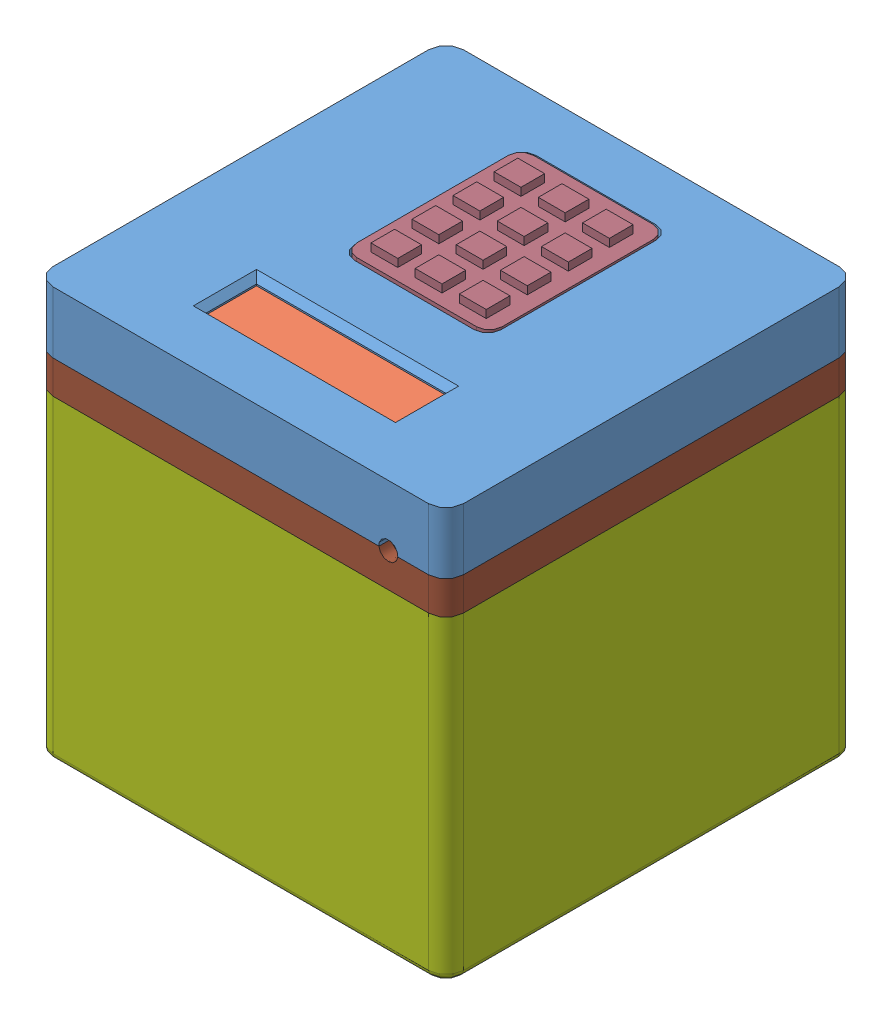
SolidWorks assembly Housing ASSY ALL, configuration Default. Lengths in mm.
Overall size (138.97 132.9 133.29).
197 component instances, 47 part files, 16 mates.
Components (placement in the parent):
- Housing ASSY TOP-1: Housing ASSY TOP [Default] at (34.8394 204.6512 120.8885) x (1 0 0) z (0 0 -1) size (130 68.9 130)
  - Housing-Top-1: Housing-Top [Default] at (0.5206 130 -0.9544) size (130 20 130)
  - LCD cover-1: LCD cover [Default] at (0.5206 132.5 -38.9544) size (83 2.5 39)
  - PCB ASSY-2: PCB ASSY [Default] at (-38.2241 57.9274 36.8538) x (1 0 0) z (0 1 0) size (111.4 79.3 20.98)
    - pcb-1: pcb [Default] at (-55.2553 -31.6918 89.0126) size (111.4 79.3 4.54)
    - pin header double row- 20 contacts-2: pin header double row- 20 contacts [Default] at (31.3735 92.5733 87.6126) x (1 0 0) z (0 1 0) size (2.54 11.54 2.54)
    - pin header double row- 20 contacts-28: pin header double row- 20 contacts [Default] at (33.9135 92.5733 87.6126) x (1 0 0) z (0 1 0) size (2.54 11.54 2.54)
    - pin header double row- 20 contacts-29: pin header double row- 20 contacts [Default] at (36.4535 92.5733 87.6126) x (1 0 0) z (0 1 0) size (2.54 11.54 2.54)
    - pin header double row- 20 contacts-30: pin header double row- 20 contacts [Default] at (38.9935 92.5733 87.6126) x (1 0 0) z (0 1 0) size (2.54 11.54 2.54)
    - pin header double row- 20 contacts-31: pin header double row- 20 contacts [Default] at (41.5335 92.5733 87.6126) x (1 0 0) z (0 1 0) size (2.54 11.54 2.54)
    - pin header double row- 20 contacts-32: pin header double row- 20 contacts [Default] at (44.0735 92.5733 87.6126) x (1 0 0) z (0 1 0) size (2.54 11.54 2.54)
    - pin header double row- 20 contacts-33: pin header double row- 20 contacts [Default] at (46.6135 92.5733 87.6126) x (1 0 0) z (0 1 0) size (2.54 11.54 2.54)
    - pin header double row- 20 contacts-34: pin header double row- 20 contacts [Default] at (49.1535 92.5733 87.6126) x (1 0 0) z (0 1 0) size (2.54 11.54 2.54)
    - pin header double row- 20 contacts-35: pin header double row- 20 contacts [Default] at (51.6935 92.5733 87.6126) x (1 0 0) z (0 1 0) size (2.54 11.54 2.54)
    - pin header double row- 20 contacts-36: pin header double row- 20 contacts [Default] at (54.2335 92.5733 87.6126) x (1 0 0) z (0 1 0) size (2.54 11.54 2.54)
    - pin header double row- 20 contacts-37: pin header double row- 20 contacts [Default] at (56.7735 92.5733 87.6126) x (1 0 0) z (0 1 0) size (2.54 11.54 2.54)
    - pin header double row- 20 contacts-38: pin header double row- 20 contacts [Default] at (59.3135 92.5733 87.6126) x (1 0 0) z (0 1 0) size (2.54 11.54 2.54)
    - pin header double row- 20 contacts-39: pin header double row- 20 contacts [Default] at (61.8535 92.5733 87.6126) x (1 0 0) z (0 1 0) size (2.54 11.54 2.54)
    - pin header double row- 20 contacts-40: pin header double row- 20 contacts [Default] at (64.3935 92.5733 87.6126) x (1 0 0) z (0 1 0) size (2.54 11.54 2.54)
    - pin header double row- 20 contacts-41: pin header double row- 20 contacts [Default] at (66.9335 92.5733 87.6126) x (1 0 0) z (0 1 0) size (2.54 11.54 2.54)
    - pin header double row- 20 contacts-42: pin header double row- 20 contacts [Default] at (69.4735 92.5733 87.6126) x (1 0 0) z (0 1 0) size (2.54 11.54 2.54)
    - pj-072c-smt-1: pj-072c-smt [Default] at (85.4947 95.3082 91.3126) x (-1 0 0) z (0 1 0) size (5.8 5.75 10.4)
      - pj-072c-smt_01-1: pj-072c-smt_01 [Default] at origin size (5.8 5.75 3.2)
      - pj-072c-smt_02-1: pj-072c-smt_02 [Default] at origin size (1.2 3 3.2)
      - pj-072c-smt_03-1: pj-072c-smt_03 [Default] at origin size (1.45 4.4 3.2)
      - pj-072c-smt_04-1: pj-072c-smt_04 [Default] at origin size (5.7 5.75 9.6)
    - LCD spacer-1: LCD spacer [Default] at (76.2447 91.3082 87.6126) x (0 1 0) z (-1 0 0) size (5 2.54 5)
    - LCD spacer-2: LCD spacer [Default] at (76.2447 60.3082 85.0726) x (1 0 0) z (0 -1 0) size (5 2.54 5)
    - LCD spacer-3: LCD spacer [Default] at (1.2447 60.3082 85.0726) x (1 0 0) z (0 -1 0) size (5 2.54 5)
    - LCD spacer-4: LCD spacer [Default] at (1.2447 91.3082 85.0726) x (1 0 0) z (0 -1 0) size (5 2.54 5)
    - 16x2 Lcd display dsgn arch 2016-edit-00-1: 16x2 Lcd display dsgn arch 2016-edit-00 [Default] at (38.7447 75.8082 83.5726) x (1 0 0) z (0 0 -1) size (80 36 8.5)
    - pin header double row- 20 contacts-43: pin header double row- 20 contacts [Default] at (45.0911 54.5782 87.6126) x (1 0 0) z (0 1 0) size (2.54 11.54 2.54)
    - pin header double row- 20 contacts-44: pin header double row- 20 contacts [Default] at (42.5511 54.5782 87.6126) x (1 0 0) z (0 1 0) size (2.54 11.54 2.54)
    - pin header double row- 20 contacts-45: pin header double row- 20 contacts [Default] at (40.0111 54.5782 87.6126) x (1 0 0) z (0 1 0) size (2.54 11.54 2.54)
    - pin header double row- 20 contacts-46: pin header double row- 20 contacts [Default] at (37.4711 54.5782 87.6126) x (1 0 0) z (0 1 0) size (2.54 11.54 2.54)
    - pin header double row- 20 contacts-47: pin header double row- 20 contacts [Default] at (34.9311 54.5782 87.6126) x (1 0 0) z (0 1 0) size (2.54 11.54 2.54)
    - pin header double row- 20 contacts-48: pin header double row- 20 contacts [Default] at (32.3911 54.5782 87.6126) x (1 0 0) z (0 1 0) size (2.54 11.54 2.54)
    - pin header double row- 20 contacts-49: pin header double row- 20 contacts [Default] at (29.8511 54.5782 87.6126) x (1 0 0) z (0 1 0) size (2.54 11.54 2.54)
    - pin header double row- 20 contacts-50: pin header double row- 20 contacts [Default] at (-3.1653 45.0418 89.0126) x (1 0 0) z (0 -1 0) size (2.54 11.54 2.54)
    - pin header double row- 20 contacts-51: pin header double row- 20 contacts [Default] at (-1.3422 35.5094 89.0126) x (1 0 0) z (0 -1 0) size (2.54 11.54 2.54)
    - pin header double row- 20 contacts-52: pin header double row- 20 contacts [Default] at (-0.4792 26.6283 89.0126) x (1 0 0) z (0 -1 0) size (2.54 11.54 2.54)
    - pin header double row- 20 contacts-53: pin header double row- 20 contacts [Default] at (17.5747 25.2818 89.0126) x (1 0 0) z (0 -1 0) size (2.54 11.54 2.54)
    - pin header double row- 20 contacts-54: pin header double row- 20 contacts [Default] at (21.0383 25.2782 89.0126) x (1 0 0) z (0 -1 0) size (2.54 11.54 2.54)
    - pin header double row- 20 contacts-55: pin header double row- 20 contacts [Default] at (-0.6253 45.0418 89.0126) x (1 0 0) z (0 -1 0) size (2.54 11.54 2.54)
    - pin header double row- 20 contacts-56: pin header double row- 20 contacts [Default] at (1.9147 45.0418 89.0126) x (1 0 0) z (0 -1 0) size (2.54 11.54 2.54)
    - pin header double row- 20 contacts-57: pin header double row- 20 contacts [Default] at (1.1978 35.5094 89.0126) x (1 0 0) z (0 -1 0) size (2.54 11.54 2.54)
    - pin header double row- 20 contacts-58: pin header double row- 20 contacts [Default] at (2.0608 26.6283 89.0126) x (1 0 0) z (0 -1 0) size (2.54 11.54 2.54)
    - pin header double row- 20 contacts-59: pin header double row- 20 contacts [Default] at (4.6008 26.6283 89.0126) x (1 0 0) z (0 -1 0) size (2.54 11.54 2.54)
    - pin header double row- 20 contacts-60: pin header double row- 20 contacts [Default] at (23.5783 25.2782 89.0126) x (1 0 0) z (0 -1 0) size (2.54 11.54 2.54)
    - pin header double row- 20 contacts-61: pin header double row- 20 contacts [Default] at (21.0383 22.7382 89.0126) x (1 0 0) z (0 -1 0) size (2.54 11.54 2.54)
    - pin header double row- 20 contacts-62: pin header double row- 20 contacts [Default] at (23.5783 22.7382 89.0126) x (1 0 0) z (0 -1 0) size (2.54 11.54 2.54)
    - pin header double row- 20 contacts-63: pin header double row- 20 contacts [Default] at (21.0383 20.1982 89.0126) x (1 0 0) z (0 -1 0) size (2.54 11.54 2.54)
    - pin header double row- 20 contacts-64: pin header double row- 20 contacts [Default] at (23.5783 20.1982 89.0126) x (1 0 0) z (0 -1 0) size (2.54 11.54 2.54)
    - pin header double row- 20 contacts-65: pin header double row- 20 contacts [Default] at (21.0383 17.6582 89.0126) x (1 0 0) z (0 -1 0) size (2.54 11.54 2.54)
    - pin header double row- 20 contacts-66: pin header double row- 20 contacts [Default] at (23.5783 17.6582 89.0126) x (1 0 0) z (0 -1 0) size (2.54 11.54 2.54)
    - pin header double row- 20 contacts-67: pin header double row- 20 contacts [Default] at (15.0347 25.2818 89.0126) x (1 0 0) z (0 -1 0) size (2.54 11.54 2.54)
    - pin header double row- 20 contacts-68: pin header double row- 20 contacts [Default] at (17.5747 22.7418 89.0126) x (1 0 0) z (0 -1 0) size (2.54 11.54 2.54)
    - pin header double row- 20 contacts-69: pin header double row- 20 contacts [Default] at (15.0347 22.7418 89.0126) x (1 0 0) z (0 -1 0) size (2.54 11.54 2.54)
    - pin header double row- 20 contacts-70: pin header double row- 20 contacts [Default] at (17.5747 20.2018 89.0126) x (1 0 0) z (0 -1 0) size (2.54 11.54 2.54)
    - pin header double row- 20 contacts-71: pin header double row- 20 contacts [Default] at (15.0347 20.2018 89.0126) x (1 0 0) z (0 -1 0) size (2.54 11.54 2.54)
    - pin header double row- 20 contacts-72: pin header double row- 20 contacts [Default] at (17.5747 17.6618 89.0126) x (1 0 0) z (0 -1 0) size (2.54 11.54 2.54)
    - pin header double row- 20 contacts-73: pin header double row- 20 contacts [Default] at (15.0347 17.6618 89.0126) x (1 0 0) z (0 -1 0) size (2.54 11.54 2.54)
    - pin header double row- 20 contacts-74: pin header double row- 20 contacts [Default] at (78.3029 68.2428 89.0126) x (1 0 0) z (0 -1 0) size (2.54 11.54 2.54)
    - pin header double row- 20 contacts-75: pin header double row- 20 contacts [Default] at (75.7629 68.2428 89.0126) x (1 0 0) z (0 -1 0) size (2.54 11.54 2.54)
    - pin header double row- 20 contacts-76: pin header double row- 20 contacts [Default] at (73.2229 68.2428 89.0126) x (1 0 0) z (0 -1 0) size (2.54 11.54 2.54)
  - Housing-Middle-1: Housing-Middle [Default] at (0.5206 160 -0.9544) x (-1 0 0) z (0 0 1) size (130 49 130)
  - pan head cross recess screw_din-3: pan head cross recess screw_din [DIN EN ISO 7045 - M2.5 x 16 - Z - 16S] at (38.0206 157.1 -23.4544) x (0 -1 0) z (0 0 1) size (18.05 5 5)
  - pan head cross recess screw_din-4: pan head cross recess screw_din [DIN EN ISO 7045 - M2.5 x 16 - Z - 16S] at (-36.9794 157.1 -54.4544) x (0 -1 0) z (0 0 1) size (18.05 5 5)
  - pan head cross recess screw_din-5: pan head cross recess screw_din [DIN EN ISO 7045 - M2.5 x 16 - Z - 16S] at (38.0206 157.1 -54.4544) x (0 -1 0) z (0 0 1) size (18.05 5 5)
  - pan head cross recess screw_din-6: pan head cross recess screw_din [DIN EN ISO 7045 - M2.5 x 16 - Z - 16S] at (-36.9794 157.1 -23.4544) x (0 -1 0) z (0 0 1) size (18.05 5 5)
  - pan head cross recess screw_din-12: pan head cross recess screw_din [DIN EN ISO 7045 - M3 x 12 - Z - 12S] at (-49.2794 157.4 14.8456) x (0 -1 0) z (0 0 1) size (14.35 5.6 5.6)
  - pan head cross recess screw_din-13: pan head cross recess screw_din [DIN EN ISO 7045 - M3 x 12 - Z - 12S] at (50.2206 157.4 14.8456) x (0 -1 0) z (0 0 1) size (14.35 5.6 5.6)
  - Keypad 3x4-2: Keypad 3x4 [Default] at (0.5206 138.1 17.7769) x (-1 0 0) z (0 0 1) size (51 11 64)
  - pan head cross recess screw_din-15: pan head cross recess screw_din [DIN EN ISO 7045 - M2.2 x 6 - Z - 6S] at (23.5206 139.7 -11.7231) x (0 -1 0) z (0 0 1) size (7.57 4 4)
  - pan head cross recess screw_din-16: pan head cross recess screw_din [DIN EN ISO 7045 - M2.2 x 6 - Z - 6S] at (-22.4794 139.7 47.2769) x (0 -1 0) z (0 0 1) size (7.57 4 4)
  - pan head cross recess screw_din-17: pan head cross recess screw_din [DIN EN ISO 7045 - M2.2 x 6 - Z - 6S] at (23.5206 139.7 47.2769) x (0 -1 0) z (0 0 1) size (7.57 4 4)
  - pan head cross recess screw_din-18: pan head cross recess screw_din [DIN EN ISO 7045 - M2.2 x 6 - Z - 6S] at (-22.4794 139.7 -11.7231) x (0 -1 0) z (0 0 1) size (7.57 4 4)
  - Battery holder-2: Battery holder [Default] at (24.0822 172 -7.5089) x (-1 0 0) z (0 0 1) size (49.75 16 72.89)
  - SNZS-M2_5-6-1: SNZS-M2_5-6 [Default] at (36.5206 158.5 -39.9544) x (0 -1 0) z (0 0 1) size (6.8 4 4)
  - SNZS-M2_5-6-2: SNZS-M2_5-6 [Default] at (36.5206 158.5 24.9456) x (0 -1 0) z (0 0 1) size (6.8 4 4)
  - SNZS-M2_5-6-3: SNZS-M2_5-6 [Default] at (11.6206 158.5 24.9456) x (0 -1 0) z (0 0 1) size (6.8 4 4)
  - SNZS-M2_5-6-4: SNZS-M2_5-6 [Default] at (11.6206 158.5 -39.9544) x (0 -1 0) z (0 0 1) size (6.8 4 4)
- Housing ASSY BOTTOM-1: Housing ASSY BOTTOM [Default] at (93.7975 -43.1003 217.5356) x (-1 0 0) z (0 0 -1) size (120.15 45 120.15)
  - Housing-Bottom-1: Housing-Bottom [Default] at (58.4375 46.7515 95.6927) size (120 45 120)
  - HK 0606-1: HK 0606 [Default] at (58.4375 53.7515 95.6927) x (0 1 0) z (0 0 1) size (6 10 10)
    - HK 0606_PART1-1: HK 0606_PART1 [Default] at origin size (6 10 10)
    - HK 0606_PART2-1: HK 0606_PART2 [Default] at origin size (3.3 1.5 1.5)
    - HK 0606_PART2-2: HK 0606_PART2 [Default] x (1 0 0) z (0 0.707107 0.707107) size (3.3 1.5 1.5)
    - HK 0606_PART2-3: HK 0606_PART2 [Default] x (1 0 0) z (0 1 0) size (3.3 1.5 1.5)
    - HK 0606_PART2-4: HK 0606_PART2 [Default] x (1 0 0) z (0 0.707107 -0.707107) size (3.3 1.5 1.5)
    - HK 0606_PART2-5: HK 0606_PART2 [Default] x (1 0 0) z (0 0 -1) size (3.3 1.5 1.5)
    - HK 0606_PART2-6: HK 0606_PART2 [Default] x (1 0 0) z (0 -0.707107 -0.707107) size (3.3 1.5 1.5)
    - HK 0606_PART2-7: HK 0606_PART2 [Default] x (1 0 0) z (0 -1 0) size (3.3 1.5 1.5)
    - HK 0606_PART2-8: HK 0606_PART2 [Default] x (1 0 0) z (0 -0.707107 0.707107) size (3.3 1.5 1.5)
    - HK 0606_PART3-1: HK 0606_PART3 [Default] at origin
    - HK 0606_PART3-2: HK 0606_PART3 [Default] x (1 0 0) z (0 0.707107 0.707107)
    - HK 0606_PART3-3: HK 0606_PART3 [Default] x (1 0 0) z (0 1 0)
    - HK 0606_PART3-4: HK 0606_PART3 [Default] x (1 0 0) z (0 0.707107 -0.707107)
    - HK 0606_PART3-5: HK 0606_PART3 [Default] x (1 0 0) z (0 0 -1)
    - HK 0606_PART3-6: HK 0606_PART3 [Default] x (1 0 0) z (0 -0.707107 -0.707107)
    - HK 0606_PART3-7: HK 0606_PART3 [Default] x (1 0 0) z (0 -1 0)
    - HK 0606_PART3-8: HK 0606_PART3 [Default] x (1 0 0) z (0 -0.707107 0.707107)
  - Center gear-1: Center gear [Default] at (58.4375 59.7515 95.6927) x (-0.818283 0 0.574815) z (0.574815 0 0.818283) size (37.48 15.12 34.22)
  - Motor Stand ASSY-2: Motor Stand ASSY [Default] at (30.3718 47.9529 58.991) size (57.7 11.2 22)
    - Motor stand-1: Motor stand [Default] at (14.5557 9.9986 19.1017) x (0 -1 0) z (0 0 1) size (11.2 18.28 22)
    - PKN7EB105C motor-1: PKN7EB105C motor [Default] at (-0.4443 9.9986 19.1017) x (0 0 -1) z (0 -1 0) size (10 25.2 8)
    - SNZF-M1_4-3-TBZ-1: SNZF-M1_4-3-TBZ [Default] at (15.1057 9.9986 15.5017) x (-1 0 0) z (0 -0.147104 0.989121) size (3 2 2)
    - SNZF-M1_4-3-TBZ-2: SNZF-M1_4-3-TBZ [Default] at (15.1057 9.9986 22.7017) x (-1 0 0) z (0 -0.877398 0.479764) size (3 2 2)
    - Worm 21-1: Worm 21 [GearTrax] at (28.0557 9.9986 19.1017) x (0 0 -1) z (1 0 0) size (6 6 21.1)
    - 10mm shaft-1: 10mm shaft [Default] at (32.0557 9.9986 19.1017) x (0 0.407305 0.913292) z (1 0 0) size (1 1 10)
    - W 618_1-1: W 618_1 [Default] at (38.1557 9.9986 19.1017) size (1 3 3)
      - W 618_1_PART1-1: W 618_1_PART1 [Default] at origin size (1 1.55 1.55)
      - W 618_1_PART2-1: W 618_1_PART2 [Default] at origin size (1 3 3)
      - W 618_1_PART3-1: W 618_1_PART3 [Default] at origin size (0.6 0.6 0.6)
      - W 618_1_PART3-2: W 618_1_PART3 [Default] x (1 0 0) z (0 0.866025 0.5) size (0.6 0.6 0.6)
      - W 618_1_PART3-3: W 618_1_PART3 [Default] x (1 0 0) z (0 0.866025 -0.5) size (0.6 0.6 0.6)
      - W 618_1_PART3-4: W 618_1_PART3 [Default] x (1 0 0) z (0 0 -1) size (0.6 0.6 0.6)
      - W 618_1_PART3-5: W 618_1_PART3 [Default] x (1 0 0) z (0 -0.866025 -0.5) size (0.6 0.6 0.6)
      - W 618_1_PART3-6: W 618_1_PART3 [Default] x (1 0 0) z (0 -0.866025 0.5) size (0.6 0.6 0.6)
    - Bearing stand-2: Bearing stand [Default] at (40.2557 9.9986 19.1017) x (0 0 1) z (-1 0 0) size (5 8.7 17)
  - countersunk flat head cross recess screw_iso-1: countersunk flat head cross recess screw_iso [ISO 7046-1 - M2.5 x 4 - Z - 4S] at (41.5775 53.9515 86.0927) x (0 -1 0) z (0.986483 0 -0.163866) size (4 4.7 4.7)
  - countersunk flat head cross recess screw_iso-2: countersunk flat head cross recess screw_iso [ISO 7046-1 - M2.5 x 4 - Z - 4S] at (75.6275 54.2515 78.0927) x (0 -1 0) z (0.994864 0 -0.10122) size (4 4.7 4.7)
  - countersunk flat head cross recess screw_iso-3: countersunk flat head cross recess screw_iso [ISO 7046-1 - M2.5 x 4 - Z - 4S] at (41.5775 53.9515 70.0927) x (0 -1 0) z (0.998701 0 -0.050963) size (4 4.7 4.7)
  - countersunk flat head cross recess screw_iso-4: countersunk flat head cross recess screw_iso [ISO 7046-1 - M2.5 x 4 - Z - 4S] at (32.4775 53.9515 86.0927) x (0 -1 0) z (0 0 1) size (4 4.7 4.7)
  - countersunk flat head cross recess screw_iso-5: countersunk flat head cross recess screw_iso [ISO 7046-1 - M2.5 x 4 - Z - 4S] at (32.4775 53.9515 70.0927) x (0 -1 0) z (-0.882562 0 0.470195) size (4 4.7 4.7)
  - countersunk flat head cross recess screw_iso-6: countersunk flat head cross recess screw_iso [ISO 7046-1 - M2.5 x 4 - Z - 4S] at (80.6275 54.2515 78.0927) x (0 -1 0) z (0 0 1) size (4 4.7 4.7)
  - SEQ-M3-6-TZB-1: SEQ-M3-6-TZB [Default] at (58.4375 60.5515 95.6927) x (0 -1 0) z (0 0 1) size (6.8 7 7)
  - plain washer 10673 type snl_iso-4: plain washer 10673 type snl_iso [ISO 10673-3.2-L] at (58.4375 59.7515 95.6927) x (0 1 0) z (0.0196 0 -0.999808) size (0.8 11 11)
  - Locking insert-1: Locking insert [Default] at (0.1058 63.8715 95.6927) x (1 0 0) z (0 -1 0) size (18.71 19 4.86)
  - Locking insert-2: Locking insert [Default] at (58.4375 63.8715 37.3608) x (0 0 1) z (0 -1 0) size (18.71 19 4.86)
  - Locking insert-3: Locking insert [Default] at (58.4375 63.8715 154.0246) x (0 0 -1) z (0 -1 0) size (18.71 19 4.86)
  - Locking insert-4: Locking insert [Default] at (116.7696 63.8715 95.6927) x (-1 0 0) z (0 -1 0) size (18.71 19 4.86)
  - LightInterrupter ASSY-1: LightInterrupter ASSY [Default] at (106.8605 54.653 115.9706) x (0 1 0) z (-1 0 0) size (27.79 23.15 13.77)
    - light interrupter-1: light interrupter [Default] at (-28.3605 -96.0125 19.17) size (23.5 8.4 2.42)
    - OPB840L51-1: OPB840L51 [Default] at (3.5735 12.3185 19.17) x (1 0 0) z (0 -1 0) size (12.95 13.04 23.15)
    - Pin Header 1x3 TH Angle Pitch 2.54mm-1: Pin Header 1x3 TH Angle Pitch 2.54mm [Default] at (14.0957 9.7707 19.1411) x (0 1 0) z (0 0 1) size (7.63 11.11 6.29)
  - Lock lever 25-1: Lock lever 25 [Default] at (48.8375 63.8715 60.3329) x (-0.768003 0 0.640446) z (-0.640446 0 -0.768003) size (31.2 2 6.2)
  - Lock lever 25-2: Lock lever 25 [Default] at (93.7975 63.8715 86.0927) x (-0.640452 0 -0.767999) z (0.767999 0 -0.640452) size (31.2 2 6.2)
  - Lock lever 25-3: Lock lever 25 [Default] at (23.0778 63.8715 105.2928) x (-0.640443 0 -0.768006) z (0.768006 0 -0.640443) size (31.2 2 6.2)
  - Lock lever 25-4: Lock lever 25 [Default] at (68.0376 63.8715 131.0525) x (0.768001 0 -0.640448) z (0.640448 0 0.768001) size (31.2 2 6.2)
  - LightInterrupter ASSY-2: LightInterrupter ASSY [Default] at (43.6894 54.653 145.0604) x (0 1 0) z (0 0 -1) size (27.79 23.15 13.77)
    - light interrupter-1: light interrupter [Default] at (-28.3605 -96.0125 19.17) size (23.5 8.4 2.42)
    - OPB840L51-1: OPB840L51 [Default] at (3.5735 12.3185 19.17) x (1 0 0) z (0 -1 0) size (12.95 13.04 23.15)
    - Pin Header 1x3 TH Angle Pitch 2.54mm-1: Pin Header 1x3 TH Angle Pitch 2.54mm [Default] at (14.0957 9.7707 19.1411) x (0 1 0) z (0 0 1) size (7.63 11.11 6.29)
  - Lock lever 23-1: Lock lever 23 [Default] at (40.8736 65.8715 108.0231) x (0.818582 0 -0.57439) z (0.57439 0 0.818582) size (29.92 12.12 6)
  - Lock lever 23-2: Lock lever 23 [Default] at (70.7679 65.8715 113.2567) x (-0.574385 0 -0.818585) z (0.818585 0 -0.574385) size (29.92 12.12 6)
  - Lock lever 23-3: Lock lever 23 [Default] at (76.0015 65.8715 83.3623) x (-0.818587 0 0.574382) z (-0.574382 0 -0.818587) size (29.92 12.12 6)
  - Lock lever 23-4: Lock lever 23 [Default] at (46.1071 65.8715 78.1287) x (0.574387 0 0.818584) z (-0.818584 0 0.574387) size (29.92 12.12 6)
  - plain washer 10673 type snl_iso-6: plain washer 10673 type snl_iso [ISO 10673-2.75-S] at (66.2112 68.8715 90.232) x (0 1 0) z (0 0 -1) size (0.6 6 6)
  - plain washer 10673 type snl_iso-7: plain washer 10673 type snl_iso [ISO 10673-2.75-S] at (63.8983 68.8715 103.4664) x (0 1 0) z (0 0 -1) size (0.6 6 6)
  - plain washer 10673 type snl_iso-8: plain washer 10673 type snl_iso [ISO 10673-2.75-S] at (50.6639 68.8715 101.1534) x (0 1 0) z (0 0 1) size (0.6 6 6)
  - plain washer 10673 type snl_iso-9: plain washer 10673 type snl_iso [ISO 10673-2.75-S] at (52.9768 68.8715 87.919) x (0 1 0) z (0 0 1) size (0.6 6 6)
  - SNZS-M2_5-6-1: SNZS-M2_5-6 [Default] at (50.6639 69.4715 101.1534) x (0 -1 0) z (0 0 1) size (6.8 4 4)
  - SNZS-M2_5-6-2: SNZS-M2_5-6 [Default] at (63.8983 69.4715 103.4664) x (0 -1 0) z (0 0 1) size (6.8 4 4)
  - SNZS-M2_5-6-3: SNZS-M2_5-6 [Default] at (52.9768 69.4715 87.919) x (0 -1 0) z (0 0 1) size (6.8 4 4)
  - SNZS-M2_5-6-4: SNZS-M2_5-6 [Default] at (66.2112 69.4715 90.232) x (0 -1 0) z (0 0 1) size (6.8 4 4)
  - plain washer 10673 type snl_iso-11: plain washer 10673 type snl_iso [ISO 10673-2.75-S] at (39.2375 63.8715 68.3385) x (0 -1 0) z (-0.982657 0 -0.185434) size (0.6 6 6)
  - plain washer 10673 type snl_iso-13: plain washer 10673 type snl_iso [ISO 10673-2.75-S] at (77.6376 63.8715 123.0469) x (0 -1 0) z (-0.441249 0 -0.897385) size (0.6 6 6)
  - plain washer 10673 type snl_iso-14: plain washer 10673 type snl_iso [ISO 10673-2.75-S] at (31.0834 63.8715 114.8928) x (0 -1 0) z (0 0 1) size (0.6 6 6)
  - plain washer 10673 type snl_iso-16: plain washer 10673 type snl_iso [ISO 10673-2.75-S] at (85.7918 63.8715 76.4927) x (0 -1 0) z (0.546944 0 -0.837169) size (0.6 6 6)
  - SNZS-M2_5-3-1: SNZS-M2_5-3 [Default] at (77.6376 63.2715 123.0469) x (0 1 0) z (0 0 1) size (3.8 4.02 4.02)
  - SNZS-M2_5-3-2: SNZS-M2_5-3 [Default] at (31.0834 63.2715 114.8928) x (0 1 0) z (0 0 1) size (3.8 4.02 4.02)
  - SNZS-M2_5-3-3: SNZS-M2_5-3 [Default] at (85.7918 63.2715 76.4927) x (0 1 0) z (0 0 1) size (3.8 4.02 4.02)
  - SNZS-M2_5-3-4: SNZS-M2_5-3 [Default] at (39.2375 63.2715 68.3385) x (0 1 0) z (0 0 1) size (3.8 4.02 4.02)
  - plain washer 10673 type snl_iso-18: plain washer 10673 type snl_iso [ISO 10673-2.75-S] at (58.4375 65.8715 52.3273) x (0 1 0) z (0 0 1) size (0.6 6 6)
  - plain washer 10673 type snl_iso-19: plain washer 10673 type snl_iso [ISO 10673-2.75-S] at (15.0723 65.8715 95.6927) x (0 1 0) z (0 0 1) size (0.6 6 6)
  - plain washer 10673 type snl_iso-20: plain washer 10673 type snl_iso [ISO 10673-2.75-S] at (58.4375 65.8715 139.0582) x (0 1 0) z (0 0 1) size (0.6 6 6)
  - plain washer 10673 type snl_iso-21: plain washer 10673 type snl_iso [ISO 10673-2.75-S] at (101.8031 65.8715 95.6927) x (0 1 0) z (-0.915769 0 0.401704) size (0.6 6 6)
  - SNZS-M2_5-3-5: SNZS-M2_5-3 [Default] at (15.0723 66.4715 95.6927) x (0 -1 0) z (0 0 1) size (3.8 4.02 4.02)
  - SNZS-M2_5-3-6: SNZS-M2_5-3 [Default] at (58.4375 66.4715 52.3273) x (0 -1 0) z (0 0 1) size (3.8 4.02 4.02)
  - SNZS-M2_5-3-7: SNZS-M2_5-3 [Default] at (101.8031 66.4715 95.6927) x (0 -1 0) z (0 0 1) size (3.8 4.02 4.02)
  - SNZS-M2_5-3-8: SNZS-M2_5-3 [Default] at (58.4375 66.4715 139.0582) x (0 -1 0) z (0 0 1) size (3.8 4.02 4.02)
  - 23 lever spacer-2: 23 lever spacer [Default] at (58.4376 69.8715 95.6927) x (0.985019 0 0.172446) z (-0.172446 0 0.985019) size (33.35 2.06 33.35)
  - plain washer normal grade a_iso-2: plain washer normal grade a_iso [Washer ISO 7089 - 1.6] at (46.1071 71.8715 78.1287) x (0 -1 0) z (0.996822 0 0.079656) size (0.3 4 4)
  - plain washer normal grade a_iso-3: plain washer normal grade a_iso [Washer ISO 7089 - 1.6] at (40.873 71.8715 108.0235) x (0 -1 0) z (0.445519 0 -0.895272) size (0.3 4 4)
  - plain washer normal grade a_iso-4: plain washer normal grade a_iso [Washer ISO 7089 - 1.6] at (70.7679 71.8715 113.2567) x (0 -1 0) z (0 0 1) size (0.3 4 4)
  - plain washer normal grade a_iso-5: plain washer normal grade a_iso [Washer ISO 7089 - 1.6] at (76.0015 71.8715 83.3623) x (0 -1 0) z (0 0 1) size (0.3 4 4)
  - SNZS-M1_6-3-5: SNZS-M1_6-3 [Default] at (76.0015 72.1715 83.3623) x (0 -1 0) z (0 0 1) size (3.5 2.3 2.3)
  - SNZS-M1_6-3-6: SNZS-M1_6-3 [Default] at (70.7679 72.1715 113.2567) x (0 -1 0) z (-0.649279 0 0.76055) size (3.5 2.3 2.3)
  - SNZS-M1_6-3-7: SNZS-M1_6-3 [Default] at (46.1071 72.1715 78.1287) x (0 -1 0) z (0 0 1) size (3.5 2.3 2.3)
  - SNZS-M1_6-3-8: SNZS-M1_6-3 [Default] at (40.8736 72.1715 108.0231) x (0 -1 0) z (0 0 1) size (3.5 2.3 2.3)
  - plain washer normal grade a_iso-10: plain washer normal grade a_iso [Washer ISO 7089 - 1.6] at (81.7255 53.7815 110.7622) x (0 -1 0) z (0.705829 0 0.708382) size (0.3 4 4)
  - plain washer normal grade a_iso-11: plain washer normal grade a_iso [Washer ISO 7089 - 1.6] at (48.8979 53.7815 119.9254) x (0 -1 0) z (0 0 1) size (0.3 4 4)
  - plain washer normal grade a_iso-12: plain washer normal grade a_iso [Washer ISO 7089 - 1.6] at (81.7255 53.7815 96.546) x (0 -1 0) z (0 0 1) size (0.3 4 4)
  - plain washer normal grade a_iso-13: plain washer normal grade a_iso [Washer ISO 7089 - 1.6] at (63.114 53.7815 119.9254) x (0 -1 0) z (0 0 1) size (0.3 4 4)
  - SNZS-M1_6-3-9: SNZS-M1_6-3 [Default] at (48.8979 54.0815 119.9254) x (0 -1 0) z (1 0 0) size (3.5 2.3 2.3)
  - SNZS-M1_6-3-10: SNZS-M1_6-3 [Default] at (81.7255 54.0815 96.546) x (0 -1 0) z (0 0 1) size (3.5 2.3 2.3)
  - SNZS-M1_6-3-11: SNZS-M1_6-3 [Default] at (81.7255 54.0815 110.7622) x (0 -1 0) z (0 0 1) size (3.5 2.3 2.3)
  - SNZS-M1_6-3-12: SNZS-M1_6-3 [Default] at (63.114 54.0815 119.9254) x (0 -1 0) z (0 0 1) size (3.5 2.3 2.3)
- pan head cross recess screw_iso-2: pan head cross recess screw_iso [ISO 7045 - M3 x 16 - Z - 16S] at (84.36 3.2512 72.8429) x (0 1 0) z (0.271484 0 -0.962443) size (18.35 5.6 5.6)
- pan head cross recess screw_iso-3: pan head cross recess screw_iso [ISO 7045 - M3 x 16 - Z - 16S] at (-13.64 3.2512 72.8429) x (0 1 0) z (0 0 -1) size (18.35 5.6 5.6)
- pan head cross recess screw_iso-4: pan head cross recess screw_iso [ISO 7045 - M3 x 16 - Z - 16S] at (84.36 3.2512 170.8429) x (0 1 0) z (0 0 1) size (18.35 5.6 5.6)
- pan head cross recess screw_iso-5: pan head cross recess screw_iso [ISO 7045 - M3 x 16 - Z - 16S] at (-13.64 3.2512 170.8429) x (0 1 0) z (0 0 1) size (18.35 5.6 5.6)
- Storage box-1: Storage box [Default] at (35.36 -55.3488 121.8429) size (130 100 130)
- Key-1: Key [Valor predeterminado] at (75.4035 -49.3488 100.5046) x (1 0 0) z (0 -1 0) size (54.6 23.6 2.71)
- PALAM-1: PALAM [Default] at (53.997 -51.3488 153.0076) x (-0.265853 0 0.964014) z (-0.964014 0 -0.265853) size (41.61 5.31 86.26)
- Warded Key 01-1: Warded Key 01 [Default] at (60.915 -46.8632 118.7113) x (0.5 0 0.866025) z (0 1 0) size (127.63 41.74 11.18)
Mates (geometry in assembly coordinates):
- Distance1: distance = 0.25 mm anti-aligned: plane of Housing ASSY BOTTOM-1/Housing-Bottom-1 through (-24.39 44.6512 181.5929) normal (-1 0 0); plane of Housing ASSY TOP-1/Housing-Middle-1 through (-24.64 48.6512 181.8429) normal (1 0 0)
- Distance2: distance = 0.25 mm anti-aligned: plane of Housing ASSY BOTTOM-1/Housing-Bottom-1 through (-24.39 44.6512 181.5929) normal (0 0 1); plane of Housing ASSY TOP-1/Housing-Middle-1 through (95.36 48.6512 181.8429) normal (0 0 -1)
- Coincident9: coincident anti-aligned: plane of Housing ASSY TOP-1/Housing-Middle-1 through (35.36 48.6512 121.8429) normal (0 -1 0); plane of Housing ASSY BOTTOM-1/Housing-Bottom-1 through (35.36 48.6512 121.8429) normal (0 1 0)
- Concentric1: concentric anti-aligned: cylinder of Housing ASSY BOTTOM-1/Housing-Bottom-1 through (84.36 3.6512 72.8429) axis (0 1 0) radius 1.5; cylinder of pan head cross recess screw_iso-2 through (84.36 -22.1488 72.8429) axis (0 -1 0) radius 2.8
- Coincident10: coincident anti-aligned: plane of Housing ASSY BOTTOM-1/Housing-Bottom-1 through (84.36 5.6512 72.8429) normal (0 -1 0); plane of pan head cross recess screw_iso-2 through (85.8036 5.6512 73.2501) normal (0 1 0)
- Concentric2: concentric aligned: cylinder of Housing ASSY BOTTOM-1/Housing-Bottom-1 through (-13.64 5.6512 72.8429) axis (0 -1 0) radius 3; cylinder of pan head cross recess screw_iso-3 through (-13.64 -22.1488 72.8429) axis (0 -1 0) radius 2.8
- Coincident11: coincident anti-aligned: plane of Housing ASSY BOTTOM-1/Housing-Bottom-1 through (-13.64 5.6512 72.8429) normal (0 -1 0); plane of pan head cross recess screw_iso-3 through (-12.14 5.6512 72.8429) normal (0 1 0)
- Concentric3: concentric anti-aligned: cylinder of Housing ASSY BOTTOM-1/Housing-Bottom-1 through (84.36 3.6512 170.8429) axis (0 1 0) radius 1.5; cylinder of pan head cross recess screw_iso-4 through (84.36 -22.1488 170.8429) axis (0 -1 0) radius 2.8
- Coincident12: coincident anti-aligned: plane of Housing ASSY BOTTOM-1/Housing-Bottom-1 through (84.36 5.6512 170.8429) normal (0 -1 0); plane of pan head cross recess screw_iso-4 through (82.86 5.6512 170.8429) normal (0 1 0)
- Concentric4: concentric aligned: cylinder of Housing ASSY BOTTOM-1/Housing-Bottom-1 through (-13.64 5.6512 170.8429) axis (0 -1 0) radius 3; cylinder of pan head cross recess screw_iso-5 through (-13.64 -22.1488 170.8429) axis (0 -1 0) radius 2.8
- Coincident13: coincident anti-aligned: plane of Housing ASSY BOTTOM-1/Housing-Bottom-1 through (-13.64 5.6512 170.8429) normal (0 -1 0); plane of pan head cross recess screw_iso-5 through (-15.14 5.6512 170.8429) normal (0 1 0)
- Distance4: distance = 0.5 mm anti-aligned: plane of Storage box-1 through (95.86 -51.3488 182.3429) normal (-1 0 0); plane of Housing ASSY BOTTOM-1/Housing-Bottom-1 through (95.36 48.6512 61.8429) normal (1 0 0)
- Distance5: distance = 0.5 mm anti-aligned: plane of Housing ASSY BOTTOM-1/Housing-Bottom-1 through (95.36 48.6512 181.8429) normal (0 0 1); plane of Storage box-1 through (-25.14 -51.3488 182.3429) normal (0 0 -1)
- Coincident16: coincident anti-aligned: plane of Housing ASSY TOP-1/Housing-Middle-1 through (94.86 44.6512 181.3429) normal (0 -1 0); plane of Storage box-1 through (35.36 44.6512 121.8429) normal (0 1 0)
- Coincident17: coincident anti-aligned: plane of Storage box-1 through (35.36 -51.3488 121.8429) normal (0 1 0); plane of Key-1 through (75.4035 -51.3488 100.5046) normal (0 -1 0)
- Coincident18: coincident anti-aligned: plane of Storage box-1 through (35.36 -51.3488 121.8429) normal (0 1 0); plane of PALAM-1 through (41.6983 -51.3488 159.9892) normal (0 -1 0)
